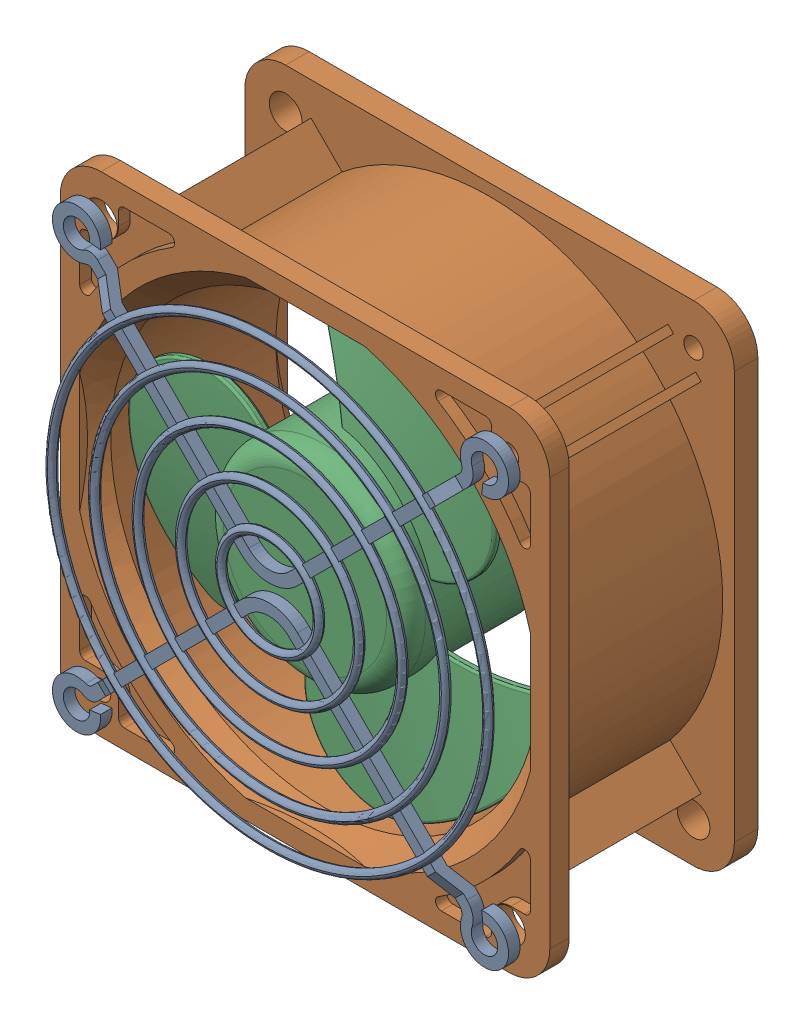
SolidWorks assembly FAN, configuration Default. Lengths in mm.
Overall size (68.56 68.39 30.36).
3 component instances, 3 part files, 0 mates.
Components (placement in the parent):
- fan_a-1: fan_a [Default] at (61.3462 -128.5644 -335.6227) x (0 0 1) z (-1 0 0) size (3.24 55.91 55.91)
- FAN_4715KL40WB30_2-1: FAN_4715KL40WB30_2 [Default] at (-170.3894 325.8656 519.6536) x (0 0 1) z (1 0 0) size (25.52 60 60)
- FAN-1-1: FAN-1 [Default] at (381.7678 -630.4988 -72.1797) x (0 0 -1) z (0.5 0.866025 0) size (17.49 50.35 49.9)
